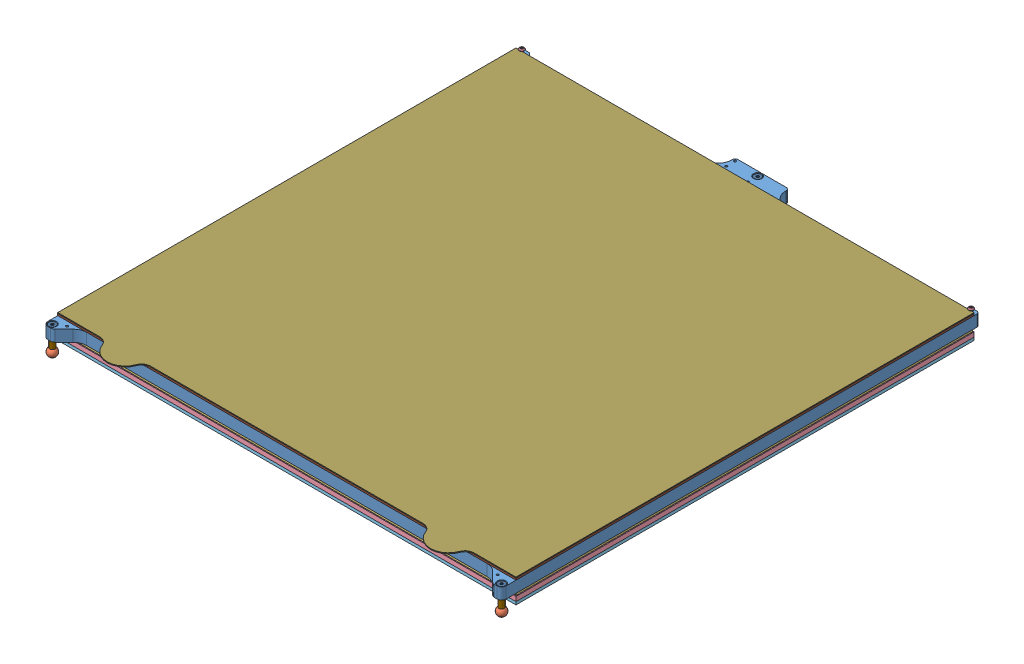
SolidWorks assembly big_z-plate_3, configuration Default. Lengths in mm.
Overall size (510.62 36.72 549.72).
77 component instances, 13 part files, 137 mates.
Components (placement in the parent):
- big_z_plate_3-1: big_z_plate_3 [V5] at origin size (510 12.7 545)
- m4_threaded_ball_10mm-1: m4_threaded_ball_10mm [Default] at (250 -19 266) size (10 9 10)
- m4_threaded_ball_10mm-2: m4_threaded_ball_10mm [Default] at (-250 -19 266) size (10 9 10)
- m4_threaded_ball_10mm-3: m4_threaded_ball_10mm [Default] at (0 -19 -269) x (0.987561 0 -0.157239) z (0.157239 0 0.987561) size (10 9 10)
- Keenovo_heater-1: Keenovo_heater [Default] at (0 -3 0) size (508 3 508)
- bed_insulation-1: bed_insulation [Default] at (0 -8 0) size (510 5 510)
- bed_insulation_clamp-1: bed_insulation_clamp [Default] at (0 -11.175 0) size (510 3.17 510)
- flat head screw_am-1: flat head screw_am [B18.6.7M - M4 x 0.7 x 30 Type I Cross Recessed FHMS --30N] at (-210 12.45 217) x (0 -1 0) z (0 0 1) size (30 8.4 8.4)
- flat head screw_am-2: flat head screw_am [B18.6.7M - M4 x 0.7 x 30 Type I Cross Recessed FHMS --30N] at (-187 12.45 210) x (0 -1 0) z (0 0 1) size (30 8.4 8.4)
- flat head screw_am-3: flat head screw_am [B18.6.7M - M4 x 0.7 x 30 Type I Cross Recessed FHMS --30N] at (-86 12.45 210) x (0 -1 0) z (0 0 1) size (30 8.4 8.4)
- flat head screw_am-4: flat head screw_am [B18.6.7M - M4 x 0.7 x 30 Type I Cross Recessed FHMS --30N] at (-210 12.45 116) x (0 -1 0) z (0 0 1) size (30 8.4 8.4)
- flat head screw_am-5: flat head screw_am [B18.6.7M - M4 x 0.7 x 30 Type I Cross Recessed FHMS --30N] at (-210 12.45 15) x (0 -1 0) z (0 0 1) size (30 8.4 8.4)
- flat head screw_am-6: flat head screw_am [B18.6.7M - M4 x 0.7 x 30 Type I Cross Recessed FHMS --30N] at (-210 12.45 -86) x (0 -1 0) z (0 0 1) size (30 8.4 8.4)
- flat head screw_am-7: flat head screw_am [B18.6.7M - M4 x 0.7 x 30 Type I Cross Recessed FHMS --30N] at (-210 12.45 -187) x (0 -1 0) z (0 0 1) size (30 8.4 8.4)
- flat head screw_am-8: flat head screw_am [B18.6.7M - M4 x 0.7 x 30 Type I Cross Recessed FHMS --30N] at (-217 12.45 -210) x (0 -1 0) z (0 0 1) size (30 8.4 8.4)
- flat head screw_am-9: flat head screw_am [B18.6.7M - M4 x 0.7 x 30 Type I Cross Recessed FHMS --30N] at (-116 12.45 -210) x (0 -1 0) z (0 0 1) size (30 8.4 8.4)
- flat head screw_am-10: flat head screw_am [B18.6.7M - M4 x 0.7 x 30 Type I Cross Recessed FHMS --30N] at (-15 12.45 -210) x (0 -1 0) z (0 0 1) size (30 8.4 8.4)
- flat head screw_am-11: flat head screw_am [B18.6.7M - M4 x 0.7 x 30 Type I Cross Recessed FHMS --30N] at (86 12.45 -210) x (0 -1 0) z (0 0 1) size (30 8.4 8.4)
- flat head screw_am-12: flat head screw_am [B18.6.7M - M4 x 0.7 x 30 Type I Cross Recessed FHMS --30N] at (187 12.45 -210) x (0 -1 0) z (0 0 1) size (30 8.4 8.4)
- flat head screw_am-13: flat head screw_am [B18.6.7M - M4 x 0.7 x 30 Type I Cross Recessed FHMS --30N] at (210 12.45 -217) x (0 -1 0) z (0 0 1) size (30 8.4 8.4)
- flat head screw_am-14: flat head screw_am [B18.6.7M - M4 x 0.7 x 30 Type I Cross Recessed FHMS --30N] at (210 12.45 -116) x (0 -1 0) z (0 0 1) size (30 8.4 8.4)
- flat head screw_am-15: flat head screw_am [B18.6.7M - M4 x 0.7 x 30 Type I Cross Recessed FHMS --30N] at (210 12.45 -15) x (0 -1 0) z (0 0 1) size (30 8.4 8.4)
- flat head screw_am-16: flat head screw_am [B18.6.7M - M4 x 0.7 x 30 Type I Cross Recessed FHMS --30N] at (210 12.45 86) x (0 -1 0) z (0 0 1) size (30 8.4 8.4)
- flat head screw_am-17: flat head screw_am [B18.6.7M - M4 x 0.7 x 30 Type I Cross Recessed FHMS --30N] at (210 12.45 187) x (0 -1 0) z (0 0 1) size (30 8.4 8.4)
- flat head screw_am-18: flat head screw_am [B18.6.7M - M4 x 0.7 x 30 Type I Cross Recessed FHMS --30N] at (217 12.45 210) x (0 -1 0) z (0 0 1) size (30 8.4 8.4)
- flat head screw_am-19: flat head screw_am [B18.6.7M - M4 x 0.7 x 30 Type I Cross Recessed FHMS --30N] at (116 12.45 210) x (0 -1 0) z (0 0 1) size (30 8.4 8.4)
- flat head screw_am-20: flat head screw_am [B18.6.7M - M4 x 0.7 x 30 Type I Cross Recessed FHMS --30N] at (15 12.45 210) x (0 -1 0) z (0 0 1) size (30 8.4 8.4)
- flat washer regular_am-41: flat washer regular_am [B18.22M - Plain washer, 4 mm, regular] at (-210 -11.175 217) x (0 1 0) z (0 0 1) size (1.4 12 12)
- hex nut style 1_am-1: hex nut style 1_am [B18.2.4.1M - Hex nut, Style 1,  M4 x 0.7 --D-N] at (-210 -15.775 217) x (1 0 0) z (0 -1 0) size (7 8.08 3.2)
- flat washer regular_am-42: flat washer regular_am [B18.22M - Plain washer, 4 mm, regular] at (-187 -11.175 210) x (0 1 0) z (0 0 1) size (1.4 12 12)
- hex nut style 1_am-2: hex nut style 1_am [B18.2.4.1M - Hex nut, Style 1,  M4 x 0.7 --D-N] at (-187 -15.775 210) x (1 0 0) z (0 -1 0) size (7 8.08 3.2)
- flat washer regular_am-43: flat washer regular_am [B18.22M - Plain washer, 4 mm, regular] at (-86 -11.175 210) x (0 1 0) z (0 0 1) size (1.4 12 12)
- hex nut style 1_am-3: hex nut style 1_am [B18.2.4.1M - Hex nut, Style 1,  M4 x 0.7 --D-N] at (-86 -15.775 210) x (1 0 0) z (0 -1 0) size (7 8.08 3.2)
- flat washer regular_am-44: flat washer regular_am [B18.22M - Plain washer, 4 mm, regular] at (-210 -11.175 116) x (0 1 0) z (0 0 1) size (1.4 12 12)
- hex nut style 1_am-4: hex nut style 1_am [B18.2.4.1M - Hex nut, Style 1,  M4 x 0.7 --D-N] at (-210 -15.775 116) x (1 0 0) z (0 -1 0) size (7 8.08 3.2)
- flat washer regular_am-45: flat washer regular_am [B18.22M - Plain washer, 4 mm, regular] at (-210 -11.175 15) x (0 1 0) z (0 0 1) size (1.4 12 12)
- hex nut style 1_am-5: hex nut style 1_am [B18.2.4.1M - Hex nut, Style 1,  M4 x 0.7 --D-N] at (-210 -15.775 15) x (1 0 0) z (0 -1 0) size (7 8.08 3.2)
- flat washer regular_am-46: flat washer regular_am [B18.22M - Plain washer, 4 mm, regular] at (-210 -11.175 -86) x (0 1 0) z (0 0 1) size (1.4 12 12)
- hex nut style 1_am-6: hex nut style 1_am [B18.2.4.1M - Hex nut, Style 1,  M4 x 0.7 --D-N] at (-210 -15.775 -86) x (1 0 0) z (0 -1 0) size (7 8.08 3.2)
- flat washer regular_am-47: flat washer regular_am [B18.22M - Plain washer, 4 mm, regular] at (-210 -11.175 -187) x (0 1 0) z (0 0 1) size (1.4 12 12)
- hex nut style 1_am-7: hex nut style 1_am [B18.2.4.1M - Hex nut, Style 1,  M4 x 0.7 --D-N] at (-210 -15.775 -187) x (1 0 0) z (0 -1 0) size (7 8.08 3.2)
- flat washer regular_am-48: flat washer regular_am [B18.22M - Plain washer, 4 mm, regular] at (-217 -11.175 -210) x (0 1 0) z (0 0 1) size (1.4 12 12)
- hex nut style 1_am-8: hex nut style 1_am [B18.2.4.1M - Hex nut, Style 1,  M4 x 0.7 --D-N] at (-217 -15.775 -210) x (1 0 0) z (0 -1 0) size (7 8.08 3.2)
- flat washer regular_am-49: flat washer regular_am [B18.22M - Plain washer, 4 mm, regular] at (-116 -11.175 -210) x (0 1 0) z (0 0 1) size (1.4 12 12)
- hex nut style 1_am-9: hex nut style 1_am [B18.2.4.1M - Hex nut, Style 1,  M4 x 0.7 --D-N] at (-116 -15.775 -210) x (1 0 0) z (0 -1 0) size (7 8.08 3.2)
- flat washer regular_am-50: flat washer regular_am [B18.22M - Plain washer, 4 mm, regular] at (-15 -11.175 -210) x (0 1 0) z (0 0 1) size (1.4 12 12)
- hex nut style 1_am-10: hex nut style 1_am [B18.2.4.1M - Hex nut, Style 1,  M4 x 0.7 --D-N] at (-15 -15.775 -210) x (1 0 0) z (0 -1 0) size (7 8.08 3.2)
- flat washer regular_am-51: flat washer regular_am [B18.22M - Plain washer, 4 mm, regular] at (86 -11.175 -210) x (0 1 0) z (0 0 1) size (1.4 12 12)
- hex nut style 1_am-11: hex nut style 1_am [B18.2.4.1M - Hex nut, Style 1,  M4 x 0.7 --D-N] at (86 -15.775 -210) x (1 0 0) z (0 -1 0) size (7 8.08 3.2)
- flat washer regular_am-52: flat washer regular_am [B18.22M - Plain washer, 4 mm, regular] at (187 -11.175 -210) x (0 1 0) z (0 0 1) size (1.4 12 12)
- hex nut style 1_am-12: hex nut style 1_am [B18.2.4.1M - Hex nut, Style 1,  M4 x 0.7 --D-N] at (187 -15.775 -210) x (1 0 0) z (0 -1 0) size (7 8.08 3.2)
- flat washer regular_am-53: flat washer regular_am [B18.22M - Plain washer, 4 mm, regular] at (210 -11.175 -217) x (0 1 0) z (0 0 1) size (1.4 12 12)
- hex nut style 1_am-13: hex nut style 1_am [B18.2.4.1M - Hex nut, Style 1,  M4 x 0.7 --D-N] at (210 -15.775 -217) x (1 0 0) z (0 -1 0) size (7 8.08 3.2)
- flat washer regular_am-54: flat washer regular_am [B18.22M - Plain washer, 4 mm, regular] at (210 -11.175 -116) x (0 1 0) z (0 0 1) size (1.4 12 12)
- hex nut style 1_am-14: hex nut style 1_am [B18.2.4.1M - Hex nut, Style 1,  M4 x 0.7 --D-N] at (210 -15.775 -116) x (1 0 0) z (0 -1 0) size (7 8.08 3.2)
- flat washer regular_am-55: flat washer regular_am [B18.22M - Plain washer, 4 mm, regular] at (210 -11.175 -15) x (0 1 0) z (0 0 1) size (1.4 12 12)
- hex nut style 1_am-15: hex nut style 1_am [B18.2.4.1M - Hex nut, Style 1,  M4 x 0.7 --D-N] at (210 -15.775 -15) x (1 0 0) z (0 -1 0) size (7 8.08 3.2)
- flat washer regular_am-56: flat washer regular_am [B18.22M - Plain washer, 4 mm, regular] at (210 -11.175 86) x (0 1 0) z (0 0 1) size (1.4 12 12)
- hex nut style 1_am-16: hex nut style 1_am [B18.2.4.1M - Hex nut, Style 1,  M4 x 0.7 --D-N] at (210 -15.775 86) x (1 0 0) z (0 -1 0) size (7 8.08 3.2)
- flat washer regular_am-57: flat washer regular_am [B18.22M - Plain washer, 4 mm, regular] at (210 -11.175 187) x (0 1 0) z (0 0 1) size (1.4 12 12)
- hex nut style 1_am-17: hex nut style 1_am [B18.2.4.1M - Hex nut, Style 1,  M4 x 0.7 --D-N] at (210 -15.775 187) x (1 0 0) z (0 -1 0) size (7 8.08 3.2)
- flat washer regular_am-58: flat washer regular_am [B18.22M - Plain washer, 4 mm, regular] at (217 -11.175 210) x (0 1 0) z (0 0 1) size (1.4 12 12)
- hex nut style 1_am-18: hex nut style 1_am [B18.2.4.1M - Hex nut, Style 1,  M4 x 0.7 --D-N] at (217 -15.775 210) x (1 0 0) z (0 -1 0) size (7 8.08 3.2)
- flat washer regular_am-59: flat washer regular_am [B18.22M - Plain washer, 4 mm, regular] at (116 -11.175 210) x (0 1 0) z (0 0 1) size (1.4 12 12)
- hex nut style 1_am-19: hex nut style 1_am [B18.2.4.1M - Hex nut, Style 1,  M4 x 0.7 --D-N] at (116 -15.775 210) x (1 0 0) z (0 -1 0) size (7 8.08 3.2)
- flat washer regular_am-60: flat washer regular_am [B18.22M - Plain washer, 4 mm, regular] at (15 -11.175 210) x (0 1 0) z (0 0 1) size (1.4 12 12)
- hex nut style 1_am-20: hex nut style 1_am [B18.2.4.1M - Hex nut, Style 1,  M4 x 0.7 --D-N] at (15 -15.775 210) x (1 0 0) z (0 -1 0) size (7 8.08 3.2)
- 94669A014_ALUM UNTHRD SPACER-1: 94669A014_ALUM UNTHRD SPACER [94669A014] at (0 -5 -269) x (0 0 -1) z (0 1 0) size (6 6 10)
- 92125A202_TYPE 18-8 SS FLAT-HEAD SOCKET CAP SCREW-1: 92125A202_TYPE 18-8 SS FLAT-HEAD SOCKET CAP SCREW [92125A202] at (0 12.3 -269) x (1 0 0) z (0 1 0) size (8 8 25.48)
- 94669A014_ALUM UNTHRD SPACER-2: 94669A014_ALUM UNTHRD SPACER [94669A014] at (250 -5 266) x (0.295002 0 0.955497) z (0 1 0) size (6 6 10)
- 92125A202_TYPE 18-8 SS FLAT-HEAD SOCKET CAP SCREW-2: 92125A202_TYPE 18-8 SS FLAT-HEAD SOCKET CAP SCREW [92125A202] at (250 12.3 266) x (-0.994693 0 0.102888) z (0 1 0) size (8 8 25.48)
- 94669A014_ALUM UNTHRD SPACER-3: 94669A014_ALUM UNTHRD SPACER [94669A014] at (-250 -5 266) x (0 0 -1) z (0 1 0) size (6 6 10)
- 92125A202_TYPE 18-8 SS FLAT-HEAD SOCKET CAP SCREW-3: 92125A202_TYPE 18-8 SS FLAT-HEAD SOCKET CAP SCREW [92125A202] at (-250 12.3 266) x (0.781589 0 -0.623793) z (0 1 0) size (8 8 25.48)
- 510_magnetic_sheet-1: 510_magnetic_sheet [Default] at (0 12.7 0) size (510 2 510)
- flexsteel_plate-1: flexsteel_plate [Default] at (0 15.7 0) x (-1 0 0) z (0 -1 0) size (510 530 1)
- m3_10mm_buttonhead_screw_92095A182-1: m3_10mm_buttonhead_screw_92095A182 [92095A182] at (250 17.6 -256.5) x (-0.85702 0 -0.515284) z (0 1 0) size (5.7 5.7 11.96)
- m3_10mm_buttonhead_screw_92095A182-2: m3_10mm_buttonhead_screw_92095A182 [92095A182] at (-250 17.6 -256.5) x (-0.858088 0 -0.513503) z (0 1 0) size (5.7 5.7 11.96)
Mates (geometry in assembly coordinates):
- Concentric4: concentric aligned: circle of Keenovo_heater-1; circle of bed_insulation-1
- Concentric5: concentric aligned: circle of bed_insulation-1; circle of bed_insulation_clamp-1
- Coincident9: coincident anti-aligned: plane of Keenovo_heater-1 through (0 -3 0) normal (0 -1 0); plane of bed_insulation-1 through (0 -3 0) normal (0 1 0)
- Coincident10: coincident anti-aligned: plane of bed_insulation-1 through (0 -8 0) normal (0 -1 0); plane of bed_insulation_clamp-1 through (0 -8 0) normal (0 1 0)
- Concentric6: concentric aligned: cylinder of bed_insulation-1 through (217 -3 210) axis (0 -1 0) radius 5; cylinder of bed_insulation_clamp-1 through (217 -8 210) axis (0 -1 0) radius 2.1
- Concentric7: concentric aligned: cylinder of Keenovo_heater-1 through (217 0 210) axis (0 -1 0) radius 5; cylinder of bed_insulation-1 through (217 -3 210) axis (0 -1 0) radius 5
- Coincident11: coincident anti-aligned: plane of Keenovo_heater-1 through (0 0 0) normal (0 1 0); plane of big_z_plate_3-1 through (0 0 0) normal (0 -1 0)
- Coincident15: coincident aligned: plane of big_z_plate_3-1 through (-255 12.7 -255) normal (-1 0 0); plane of bed_insulation_clamp-1 through (-255 -8 255) normal (-1 0 0)
- Coincident17: coincident aligned: plane of big_z_plate_3-1 through (-5 12.7 -255) normal (0 0 -1); plane of bed_insulation_clamp-1 through (-255 -8 -255) normal (0 0 -1)
- Coincident18: coincident aligned: cone of big_z_plate_3-1 through (-210 12.7 217) axis (0 -1 0); cone of flat head screw_am-1 through (-210 11.95 217) axis (0 -1 0)
- Coincident19: coincident aligned: cone of big_z_plate_3-1 through (-187 12.7 210) axis (0 -1 0); cone of flat head screw_am-2 through (-187 11.95 210) axis (0 -1 0)
- Coincident20: coincident aligned: cone of big_z_plate_3-1 through (-86 12.7 210) axis (0 -1 0); cone of flat head screw_am-3 through (-86 11.95 210) axis (0 -1 0)
- Coincident21: coincident aligned: cone of big_z_plate_3-1 through (-210 12.7 116) axis (0 -1 0); cone of flat head screw_am-4 through (-210 11.95 116) axis (0 -1 0)
- Coincident22: coincident aligned: cone of big_z_plate_3-1 through (-210 12.7 15) axis (0 -1 0); cone of flat head screw_am-5 through (-210 11.95 15) axis (0 -1 0)
- Coincident23: coincident aligned: cone of big_z_plate_3-1 through (-210 12.7 -86) axis (0 -1 0); cone of flat head screw_am-6 through (-210 11.95 -86) axis (0 -1 0)
- Coincident24: coincident aligned: cone of big_z_plate_3-1 through (-210 12.7 -187) axis (0 -1 0); cone of flat head screw_am-7 through (-210 11.95 -187) axis (0 -1 0)
- Coincident25: coincident aligned: cone of big_z_plate_3-1 through (-217 12.7 -210) axis (0 -1 0); cone of flat head screw_am-8 through (-217 11.95 -210) axis (0 -1 0)
- Coincident26: coincident aligned: cone of big_z_plate_3-1 through (-116 12.7 -210) axis (0 -1 0); cone of flat head screw_am-9 through (-116 11.95 -210) axis (0 -1 0)
- Coincident27: coincident aligned: cone of big_z_plate_3-1 through (-15 12.7 -210) axis (0 -1 0); cone of flat head screw_am-10 through (-15 11.95 -210) axis (0 -1 0)
- Coincident28: coincident aligned: cone of big_z_plate_3-1 through (86 12.7 -210) axis (0 -1 0); cone of flat head screw_am-11 through (86 11.95 -210) axis (0 -1 0)
- Coincident29: coincident aligned: cone of big_z_plate_3-1 through (187 12.7 -210) axis (0 -1 0); cone of flat head screw_am-12 through (187 11.95 -210) axis (0 -1 0)
- Coincident30: coincident aligned: cone of big_z_plate_3-1 through (210 12.7 -217) axis (0 -1 0); cone of flat head screw_am-13 through (210 11.95 -217) axis (0 -1 0)
- Coincident31: coincident aligned: cone of big_z_plate_3-1 through (210 12.7 -116) axis (0 -1 0); cone of flat head screw_am-14 through (210 11.95 -116) axis (0 -1 0)
- Coincident32: coincident aligned: cone of big_z_plate_3-1 through (210 12.7 -15) axis (0 -1 0); cone of flat head screw_am-15 through (210 11.95 -15) axis (0 -1 0)
- Coincident33: coincident aligned: cone of big_z_plate_3-1 through (210 12.7 86) axis (0 -1 0); cone of flat head screw_am-16 through (210 11.95 86) axis (0 -1 0)
- Coincident34: coincident aligned: cone of big_z_plate_3-1 through (210 12.7 187) axis (0 -1 0); cone of flat head screw_am-17 through (210 11.95 187) axis (0 -1 0)
- Coincident35: coincident aligned: cone of big_z_plate_3-1 through (217 12.7 210) axis (0 -1 0); cone of flat head screw_am-18 through (217 11.95 210) axis (0 -1 0)
- Coincident36: coincident aligned: cone of big_z_plate_3-1 through (116 12.7 210) axis (0 -1 0); cone of flat head screw_am-19 through (116 11.95 210) axis (0 -1 0)
- Coincident37: coincident aligned: cone of big_z_plate_3-1 through (15 12.7 210) axis (0 -1 0); cone of flat head screw_am-20 through (15 11.95 210) axis (0 -1 0)
- Concentric88: concentric anti-aligned: cylinder of flat head screw_am-1 through (-210 18.8 217) axis (0 1 0) radius 2; cylinder of flat washer regular_am-41 through (-210 -46.1 217) axis (0 -1 0) radius 2.44
- Coincident121: coincident anti-aligned: plane of bed_insulation_clamp-1 through (0 -11.175 0) normal (0 -1 0); plane of flat washer regular_am-41 through (-212.44 -11.175 217) normal (0 1 0)
- Concentric89: concentric anti-aligned: cylinder of flat head screw_am-1 through (-210 18.8 217) axis (0 1 0) radius 2; cylinder of hex nut style 1_am-1 through (-210 9.2625 217) axis (0 -1 0) radius 2
- Coincident122: coincident anti-aligned: plane of flat washer regular_am-41 through (-216 -12.575 217) normal (0 -1 0); plane of hex nut style 1_am-1 through (-210 -12.575 221.0415) normal (0 1 0)
- Concentric90: concentric anti-aligned: cylinder of flat head screw_am-2 through (-187 18.8 210) axis (0 1 0) radius 2; cylinder of flat washer regular_am-42 through (-187 -46.1 210) axis (0 -1 0) radius 2.44
- Coincident123: coincident anti-aligned: plane of bed_insulation_clamp-1 through (0 -11.175 0) normal (0 -1 0); plane of flat washer regular_am-42 through (-189.44 -11.175 210) normal (0 1 0)
- Concentric91: concentric anti-aligned: cylinder of flat head screw_am-2 through (-187 18.8 210) axis (0 1 0) radius 2; cylinder of hex nut style 1_am-2 through (-187 9.2625 210) axis (0 -1 0) radius 2
- Coincident124: coincident anti-aligned: plane of flat washer regular_am-42 through (-193 -12.575 210) normal (0 -1 0); plane of hex nut style 1_am-2 through (-187 -12.575 214.0415) normal (0 1 0)
- Concentric92: concentric anti-aligned: cylinder of flat head screw_am-3 through (-86 18.8 210) axis (0 1 0) radius 2; cylinder of flat washer regular_am-43 through (-86 -46.1 210) axis (0 -1 0) radius 2.44
- Coincident125: coincident anti-aligned: plane of bed_insulation_clamp-1 through (0 -11.175 0) normal (0 -1 0); plane of flat washer regular_am-43 through (-88.44 -11.175 210) normal (0 1 0)
- Concentric93: concentric anti-aligned: cylinder of flat head screw_am-3 through (-86 18.8 210) axis (0 1 0) radius 2; cylinder of hex nut style 1_am-3 through (-86 9.2625 210) axis (0 -1 0) radius 2
- Coincident126: coincident anti-aligned: plane of flat washer regular_am-43 through (-92 -12.575 210) normal (0 -1 0); plane of hex nut style 1_am-3 through (-86 -12.575 214.0415) normal (0 1 0)
- Concentric94: concentric anti-aligned: cylinder of flat head screw_am-4 through (-210 18.8 116) axis (0 1 0) radius 2; cylinder of flat washer regular_am-44 through (-210 -46.1 116) axis (0 -1 0) radius 2.44
- Coincident127: coincident anti-aligned: plane of bed_insulation_clamp-1 through (0 -11.175 0) normal (0 -1 0); plane of flat washer regular_am-44 through (-212.44 -11.175 116) normal (0 1 0)
- Concentric95: concentric anti-aligned: cylinder of flat head screw_am-4 through (-210 18.8 116) axis (0 1 0) radius 2; cylinder of hex nut style 1_am-4 through (-210 9.2625 116) axis (0 -1 0) radius 2
- Coincident128: coincident anti-aligned: plane of flat washer regular_am-44 through (-216 -12.575 116) normal (0 -1 0); plane of hex nut style 1_am-4 through (-210 -12.575 120.0415) normal (0 1 0)
- Concentric96: concentric anti-aligned: cylinder of flat head screw_am-5 through (-210 18.8 15) axis (0 1 0) radius 2; cylinder of flat washer regular_am-45 through (-210 -46.1 15) axis (0 -1 0) radius 2.44
- Coincident129: coincident anti-aligned: plane of bed_insulation_clamp-1 through (0 -11.175 0) normal (0 -1 0); plane of flat washer regular_am-45 through (-212.44 -11.175 15) normal (0 1 0)
- Concentric97: concentric anti-aligned: cylinder of flat head screw_am-5 through (-210 18.8 15) axis (0 1 0) radius 2; cylinder of hex nut style 1_am-5 through (-210 9.2625 15) axis (0 -1 0) radius 2
- Coincident130: coincident anti-aligned: plane of flat washer regular_am-45 through (-216 -12.575 15) normal (0 -1 0); plane of hex nut style 1_am-5 through (-210 -12.575 19.0415) normal (0 1 0)
- Concentric98: concentric anti-aligned: cylinder of flat head screw_am-6 through (-210 18.8 -86) axis (0 1 0) radius 2; cylinder of flat washer regular_am-46 through (-210 -46.1 -86) axis (0 -1 0) radius 2.44
- Coincident131: coincident anti-aligned: plane of bed_insulation_clamp-1 through (0 -11.175 0) normal (0 -1 0); plane of flat washer regular_am-46 through (-212.44 -11.175 -86) normal (0 1 0)
- Concentric99: concentric anti-aligned: cylinder of flat head screw_am-6 through (-210 18.8 -86) axis (0 1 0) radius 2; cylinder of hex nut style 1_am-6 through (-210 9.2625 -86) axis (0 -1 0) radius 2
- Coincident132: coincident anti-aligned: plane of flat washer regular_am-46 through (-216 -12.575 -86) normal (0 -1 0); plane of hex nut style 1_am-6 through (-210 -12.575 -81.9585) normal (0 1 0)
- Concentric100: concentric anti-aligned: cylinder of flat head screw_am-7 through (-210 18.8 -187) axis (0 1 0) radius 2; cylinder of flat washer regular_am-47 through (-210 -46.1 -187) axis (0 -1 0) radius 2.44
- Coincident133: coincident anti-aligned: plane of bed_insulation_clamp-1 through (0 -11.175 0) normal (0 -1 0); plane of flat washer regular_am-47 through (-212.44 -11.175 -187) normal (0 1 0)
- Concentric101: concentric anti-aligned: cylinder of flat head screw_am-7 through (-210 18.8 -187) axis (0 1 0) radius 2; cylinder of hex nut style 1_am-7 through (-210 9.2625 -187) axis (0 -1 0) radius 2
- Coincident134: coincident anti-aligned: plane of flat washer regular_am-47 through (-216 -12.575 -187) normal (0 -1 0); plane of hex nut style 1_am-7 through (-210 -12.575 -182.9585) normal (0 1 0)
- Concentric102: concentric anti-aligned: cylinder of flat head screw_am-8 through (-217 18.8 -210) axis (0 1 0) radius 2; cylinder of flat washer regular_am-48 through (-217 -46.1 -210) axis (0 -1 0) radius 2.44
- Coincident135: coincident anti-aligned: plane of bed_insulation_clamp-1 through (0 -11.175 0) normal (0 -1 0); plane of flat washer regular_am-48 through (-219.44 -11.175 -210) normal (0 1 0)
- Concentric103: concentric anti-aligned: cylinder of flat head screw_am-8 through (-217 18.8 -210) axis (0 1 0) radius 2; cylinder of hex nut style 1_am-8 through (-217 9.2625 -210) axis (0 -1 0) radius 2
- Coincident136: coincident anti-aligned: plane of flat washer regular_am-48 through (-223 -12.575 -210) normal (0 -1 0); plane of hex nut style 1_am-8 through (-217 -12.575 -205.9585) normal (0 1 0)
- Concentric104: concentric anti-aligned: cylinder of flat head screw_am-9 through (-116 18.8 -210) axis (0 1 0) radius 2; cylinder of flat washer regular_am-49 through (-116 -46.1 -210) axis (0 -1 0) radius 2.44
- Coincident137: coincident anti-aligned: plane of bed_insulation_clamp-1 through (0 -11.175 0) normal (0 -1 0); plane of flat washer regular_am-49 through (-118.44 -11.175 -210) normal (0 1 0)
- Concentric105: concentric anti-aligned: cylinder of flat head screw_am-9 through (-116 18.8 -210) axis (0 1 0) radius 2; cylinder of hex nut style 1_am-9 through (-116 9.2625 -210) axis (0 -1 0) radius 2
- Coincident138: coincident anti-aligned: plane of flat washer regular_am-49 through (-122 -12.575 -210) normal (0 -1 0); plane of hex nut style 1_am-9 through (-116 -12.575 -205.9585) normal (0 1 0)
- Concentric106: concentric anti-aligned: cylinder of flat head screw_am-10 through (-15 18.8 -210) axis (0 1 0) radius 2; cylinder of flat washer regular_am-50 through (-15 -46.1 -210) axis (0 -1 0) radius 2.44
- Coincident139: coincident anti-aligned: plane of bed_insulation_clamp-1 through (0 -11.175 0) normal (0 -1 0); plane of flat washer regular_am-50 through (-17.44 -11.175 -210) normal (0 1 0)
- Concentric107: concentric anti-aligned: cylinder of flat head screw_am-10 through (-15 18.8 -210) axis (0 1 0) radius 2; cylinder of hex nut style 1_am-10 through (-15 9.2625 -210) axis (0 -1 0) radius 2
- Coincident140: coincident anti-aligned: plane of flat washer regular_am-50 through (-21 -12.575 -210) normal (0 -1 0); plane of hex nut style 1_am-10 through (-15 -12.575 -205.9585) normal (0 1 0)
- Concentric108: concentric anti-aligned: cylinder of flat head screw_am-11 through (86 18.8 -210) axis (0 1 0) radius 2; cylinder of flat washer regular_am-51 through (86 -46.1 -210) axis (0 -1 0) radius 2.44
- Coincident141: coincident anti-aligned: plane of bed_insulation_clamp-1 through (0 -11.175 0) normal (0 -1 0); plane of flat washer regular_am-51 through (83.56 -11.175 -210) normal (0 1 0)
- Concentric109: concentric anti-aligned: cylinder of flat head screw_am-11 through (86 18.8 -210) axis (0 1 0) radius 2; cylinder of hex nut style 1_am-11 through (86 9.2625 -210) axis (0 -1 0) radius 2
- Coincident142: coincident anti-aligned: plane of flat washer regular_am-51 through (80 -12.575 -210) normal (0 -1 0); plane of hex nut style 1_am-11 through (86 -12.575 -205.9585) normal (0 1 0)
- Concentric110: concentric anti-aligned: cylinder of flat head screw_am-12 through (187 18.8 -210) axis (0 1 0) radius 2; cylinder of flat washer regular_am-52 through (187 -46.1 -210) axis (0 -1 0) radius 2.44
- Coincident143: coincident anti-aligned: plane of bed_insulation_clamp-1 through (0 -11.175 0) normal (0 -1 0); plane of flat washer regular_am-52 through (184.56 -11.175 -210) normal (0 1 0)
- Concentric111: concentric anti-aligned: cylinder of flat head screw_am-12 through (187 18.8 -210) axis (0 1 0) radius 2; cylinder of hex nut style 1_am-12 through (187 9.2625 -210) axis (0 -1 0) radius 2
- Coincident144: coincident anti-aligned: plane of flat washer regular_am-52 through (181 -12.575 -210) normal (0 -1 0); plane of hex nut style 1_am-12 through (187 -12.575 -205.9585) normal (0 1 0)
- Concentric112: concentric anti-aligned: cylinder of flat head screw_am-13 through (210 18.8 -217) axis (0 1 0) radius 2; cylinder of flat washer regular_am-53 through (210 -46.1 -217) axis (0 -1 0) radius 2.44
- Coincident145: coincident anti-aligned: plane of bed_insulation_clamp-1 through (0 -11.175 0) normal (0 -1 0); plane of flat washer regular_am-53 through (207.56 -11.175 -217) normal (0 1 0)
- Concentric113: concentric anti-aligned: cylinder of flat head screw_am-13 through (210 18.8 -217) axis (0 1 0) radius 2; cylinder of hex nut style 1_am-13 through (210 9.2625 -217) axis (0 -1 0) radius 2
- Coincident146: coincident anti-aligned: plane of flat washer regular_am-53 through (204 -12.575 -217) normal (0 -1 0); plane of hex nut style 1_am-13 through (210 -12.575 -212.9585) normal (0 1 0)
- Concentric114: concentric anti-aligned: cylinder of flat head screw_am-14 through (210 18.8 -116) axis (0 1 0) radius 2; cylinder of flat washer regular_am-54 through (210 -46.1 -116) axis (0 -1 0) radius 2.44
- Coincident147: coincident anti-aligned: plane of bed_insulation_clamp-1 through (0 -11.175 0) normal (0 -1 0); plane of flat washer regular_am-54 through (207.56 -11.175 -116) normal (0 1 0)
- Concentric115: concentric anti-aligned: cylinder of flat head screw_am-14 through (210 18.8 -116) axis (0 1 0) radius 2; cylinder of hex nut style 1_am-14 through (210 9.2625 -116) axis (0 -1 0) radius 2
- Coincident148: coincident anti-aligned: plane of flat washer regular_am-54 through (204 -12.575 -116) normal (0 -1 0); plane of hex nut style 1_am-14 through (210 -12.575 -111.9585) normal (0 1 0)
- Concentric116: concentric anti-aligned: cylinder of flat head screw_am-15 through (210 18.8 -15) axis (0 1 0) radius 2; cylinder of flat washer regular_am-55 through (210 -46.1 -15) axis (0 -1 0) radius 2.44
- Coincident149: coincident anti-aligned: plane of bed_insulation_clamp-1 through (0 -11.175 0) normal (0 -1 0); plane of flat washer regular_am-55 through (207.56 -11.175 -15) normal (0 1 0)
- Concentric117: concentric anti-aligned: cylinder of flat head screw_am-15 through (210 18.8 -15) axis (0 1 0) radius 2; cylinder of hex nut style 1_am-15 through (210 9.2625 -15) axis (0 -1 0) radius 2
- Coincident150: coincident anti-aligned: plane of flat washer regular_am-55 through (204 -12.575 -15) normal (0 -1 0); plane of hex nut style 1_am-15 through (210 -12.575 -10.9585) normal (0 1 0)
- Concentric118: concentric anti-aligned: cylinder of flat head screw_am-16 through (210 18.8 86) axis (0 1 0) radius 2; cylinder of flat washer regular_am-56 through (210 -46.1 86) axis (0 -1 0) radius 2.44
- Coincident151: coincident anti-aligned: plane of bed_insulation_clamp-1 through (0 -11.175 0) normal (0 -1 0); plane of flat washer regular_am-56 through (207.56 -11.175 86) normal (0 1 0)
- Concentric119: concentric anti-aligned: cylinder of flat head screw_am-16 through (210 18.8 86) axis (0 1 0) radius 2; cylinder of hex nut style 1_am-16 through (210 9.2625 86) axis (0 -1 0) radius 2
- Coincident152: coincident anti-aligned: plane of flat washer regular_am-56 through (204 -12.575 86) normal (0 -1 0); plane of hex nut style 1_am-16 through (210 -12.575 90.0415) normal (0 1 0)
- Concentric120: concentric anti-aligned: cylinder of flat head screw_am-17 through (210 18.8 187) axis (0 1 0) radius 2; cylinder of flat washer regular_am-57 through (210 -46.1 187) axis (0 -1 0) radius 2.44
- Coincident153: coincident anti-aligned: plane of bed_insulation_clamp-1 through (0 -11.175 0) normal (0 -1 0); plane of flat washer regular_am-57 through (207.56 -11.175 187) normal (0 1 0)
- Concentric121: concentric anti-aligned: cylinder of flat head screw_am-17 through (210 18.8 187) axis (0 1 0) radius 2; cylinder of hex nut style 1_am-17 through (210 9.2625 187) axis (0 -1 0) radius 2
- Coincident154: coincident anti-aligned: plane of flat washer regular_am-57 through (204 -12.575 187) normal (0 -1 0); plane of hex nut style 1_am-17 through (210 -12.575 191.0415) normal (0 1 0)
- Concentric122: concentric anti-aligned: cylinder of flat head screw_am-18 through (217 18.8 210) axis (0 1 0) radius 2; cylinder of flat washer regular_am-58 through (217 -46.1 210) axis (0 -1 0) radius 2.44
- Coincident155: coincident anti-aligned: plane of bed_insulation_clamp-1 through (0 -11.175 0) normal (0 -1 0); plane of flat washer regular_am-58 through (214.56 -11.175 210) normal (0 1 0)
- Concentric123: concentric anti-aligned: cylinder of flat head screw_am-18 through (217 18.8 210) axis (0 1 0) radius 2; cylinder of hex nut style 1_am-18 through (217 9.2625 210) axis (0 -1 0) radius 2
- Coincident156: coincident anti-aligned: plane of flat washer regular_am-58 through (211 -12.575 210) normal (0 -1 0); plane of hex nut style 1_am-18 through (217 -12.575 214.0415) normal (0 1 0)
- Concentric124: concentric anti-aligned: cylinder of flat head screw_am-19 through (116 18.8 210) axis (0 1 0) radius 2; cylinder of flat washer regular_am-59 through (116 -46.1 210) axis (0 -1 0) radius 2.44
- Coincident157: coincident anti-aligned: plane of bed_insulation_clamp-1 through (0 -11.175 0) normal (0 -1 0); plane of flat washer regular_am-59 through (113.56 -11.175 210) normal (0 1 0)
- Concentric125: concentric anti-aligned: cylinder of flat head screw_am-19 through (116 18.8 210) axis (0 1 0) radius 2; cylinder of hex nut style 1_am-19 through (116 9.2625 210) axis (0 -1 0) radius 2
- Coincident158: coincident anti-aligned: plane of flat washer regular_am-59 through (110 -12.575 210) normal (0 -1 0); plane of hex nut style 1_am-19 through (116 -12.575 214.0415) normal (0 1 0)
- Concentric126: concentric anti-aligned: cylinder of flat head screw_am-20 through (15 18.8 210) axis (0 1 0) radius 2; cylinder of flat washer regular_am-60 through (15 -46.1 210) axis (0 -1 0) radius 2.44
- Coincident159: coincident anti-aligned: plane of bed_insulation_clamp-1 through (0 -11.175 0) normal (0 -1 0); plane of flat washer regular_am-60 through (12.56 -11.175 210) normal (0 1 0)
- Concentric127: concentric anti-aligned: cylinder of flat head screw_am-20 through (15 18.8 210) axis (0 1 0) radius 2; cylinder of hex nut style 1_am-20 through (15 9.2625 210) axis (0 -1 0) radius 2
- Coincident160: coincident anti-aligned: plane of flat washer regular_am-60 through (9 -12.575 210) normal (0 -1 0); plane of hex nut style 1_am-20 through (15 -12.575 214.0415) normal (0 1 0)
- Coincident162: coincident anti-aligned: plane of big_z_plate_3-1 through (0 0 0) normal (0 -1 0); plane of 94669A014_ALUM UNTHRD SPACER-1 through (0 0 -269) normal (0 1 0)
- Concentric130: concentric aligned: circle of big_z_plate_3-1; circle of 92125A202_TYPE 18-8 SS FLAT-HEAD SOCKET CAP SCREW-1
- Coincident165: coincident aligned: cone of big_z_plate_3-1 through (0 12.7 -269) axis (0 -1 0); cone of 92125A202_TYPE 18-8 SS FLAT-HEAD SOCKET CAP SCREW-1 through (0 10 -269) axis (0 -1 0)
- Concentric131: concentric aligned: circle of big_z_plate_3-1; circle of 92125A202_TYPE 18-8 SS FLAT-HEAD SOCKET CAP SCREW-2
- Coincident166: coincident aligned: cone of big_z_plate_3-1 through (250 12.7 266) axis (0 -1 0); cone of 92125A202_TYPE 18-8 SS FLAT-HEAD SOCKET CAP SCREW-2 through (250 10 266) axis (0 -1 0)
- Coincident167: coincident anti-aligned: plane of big_z_plate_3-1 through (0 0 0) normal (0 -1 0); plane of 94669A014_ALUM UNTHRD SPACER-2 through (250 0 266) normal (0 1 0)
- Coincident171: coincident anti-aligned: plane of big_z_plate_3-1 through (0 0 0) normal (0 -1 0); plane of 94669A014_ALUM UNTHRD SPACER-1 through (0 0 -269) normal (0 1 0)
- Concentric135: concentric aligned: circle of big_z_plate_3-1; circle of 94669A014_ALUM UNTHRD SPACER-1
- Coincident180: coincident anti-aligned: plane of m4_threaded_ball_10mm-2 through (-250 -10 266) normal (0 1 0); plane of 94669A014_ALUM UNTHRD SPACER-3 through (-250 -10 266) normal (0 -1 0)
- Concentric139: concentric anti-aligned: circle of m4_threaded_ball_10mm-2; circle of 94669A014_ALUM UNTHRD SPACER-3
- Concentric140: concentric aligned: circle of big_z_plate_3-1; circle of 92125A202_TYPE 18-8 SS FLAT-HEAD SOCKET CAP SCREW-3
- Coincident182: coincident aligned: cone of big_z_plate_3-1 through (-250 12.7 266) axis (0 -1 0); cone of 92125A202_TYPE 18-8 SS FLAT-HEAD SOCKET CAP SCREW-3 through (-250 10 266) axis (0 -1 0)
- Coincident183: coincident anti-aligned: plane of big_z_plate_3-1 through (0 0 0) normal (0 -1 0); plane of 94669A014_ALUM UNTHRD SPACER-3 through (-250 0 266) normal (0 1 0)
- Concentric141: concentric anti-aligned: circle of big_z_plate_3-1; cylinder of 94669A014_ALUM UNTHRD SPACER-3 through (-250 0 266) axis (0 -1 0) radius 3
- Coincident184: coincident anti-aligned: plane of m4_threaded_ball_10mm-1 through (250 -10 266) normal (0 1 0); plane of 94669A014_ALUM UNTHRD SPACER-2 through (250 -10 266) normal (0 -1 0)
- Concentric142: concentric anti-aligned: circle of m4_threaded_ball_10mm-1; circle of 94669A014_ALUM UNTHRD SPACER-2
- Coincident186: coincident anti-aligned: plane of big_z_plate_3-1 through (0 0 0) normal (0 -1 0); plane of 94669A014_ALUM UNTHRD SPACER-2 through (250 0 266) normal (0 1 0)
- Concentric143: concentric aligned: circle of big_z_plate_3-1; circle of 94669A014_ALUM UNTHRD SPACER-2
- Coincident187: coincident anti-aligned: plane of big_z_plate_3-1 through (0 12.7 0) normal (0 1 0); plane of 510_magnetic_sheet-1 through (0 12.7 0) normal (0 -1 0)
- Coincident188: coincident aligned: plane of big_z_plate_3-1 through (5 12.7 -255) normal (0 0 -1); plane of 510_magnetic_sheet-1 through (-255 14.7 -255) normal (0 0 -1)
- Coincident189: coincident aligned: plane of big_z_plate_3-1 through (255 12.7 -255) normal (1 0 0); plane of 510_magnetic_sheet-1 through (255 14.7 255) normal (1 0 0)
- Coincident190: coincident anti-aligned: plane of 510_magnetic_sheet-1 through (0 14.7 0) normal (0 1 0); plane of flexsteel_plate-1 through (208.2843 14.7 265) normal (0 -1 0)
- Coincident191: coincident aligned: plane of big_z_plate_3-1 through (5 12.7 -255) normal (0 0 -1); plane of flexsteel_plate-1 through (255 14.7 -255) normal (0 0 -1)
- Coincident192: coincident aligned: plane of big_z_plate_3-1 through (255 12.7 -255) normal (1 0 0); plane of flexsteel_plate-1 through (255 14.7 255) normal (1 0 0)
- Concentric144: concentric aligned: circle of big_z_plate_3-1; circle of m3_10mm_buttonhead_screw_92095A182-1
- Distance1: distance = 0.25 mm anti-aligned: plane of m3_10mm_buttonhead_screw_92095A182-1 through (251.4686 15.95 -258.9425) normal (0 -1 0); plane of flexsteel_plate-1 through (208.2843 15.7 265) normal (0 1 0)
- Concentric145: concentric aligned: circle of big_z_plate_3-1; circle of m3_10mm_buttonhead_screw_92095A182-2
- Distance2: distance = 0.25 mm anti-aligned: plane of flexsteel_plate-1 through (208.2843 15.7 265) normal (0 1 0); plane of m3_10mm_buttonhead_screw_92095A182-2 through (-248.5365 15.95 -258.9456) normal (0 -1 0)
